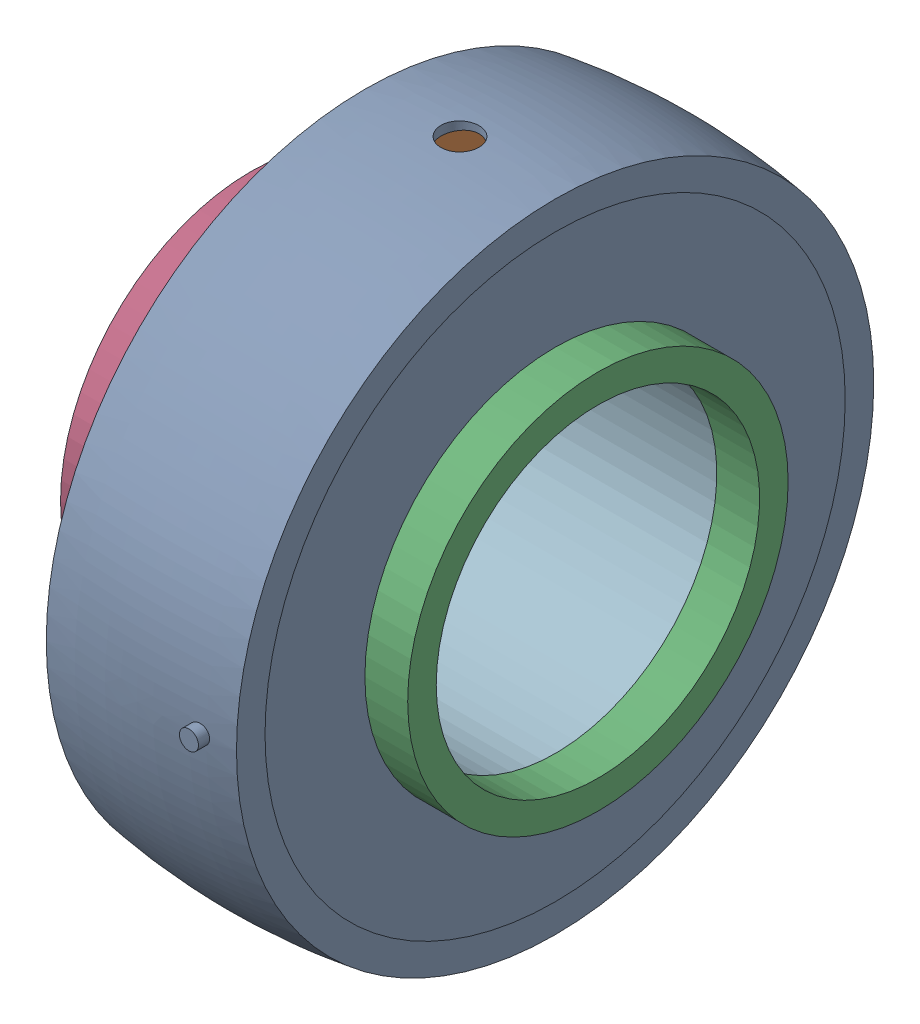
SolidWorks assembly PB bearing, configuration Default. Lengths in mm.
Overall size (36.5 72.34 70.23).
16 component instances, 6 part files, 0 mates.
Components (placement in the parent):
- PB outer-1: PB outer [Default] at origin size (20 68.56 69.24)
- PB Ball-1: PB Ball [Default] at (0 -4.1637 -25.6644) x (1 0 0) z (0 -0.951057 -0.309017) size (15 15 15)
- PB Ball-2: PB Ball [Default] at (0 -25.695 -3.9709) x (1 0 0) z (0 -0.587785 0.809017) size (15 15 15)
- PB Ball-3: PB Ball [Default] at (0 25.695 3.9709) x (1 0 0) z (0 0.587785 -0.809017) size (15 15 15)
- PB Ball-4: PB Ball [Default] at (0 -11.7167 23.2103) x (1 0 0) z (0 0.587785 0.809017) size (15 15 15)
- PB Ball-5: PB Ball [Default] at (0 11.7167 -23.2103) x (1 0 0) z (0 -0.587785 -0.809017) size (15 15 15)
- PB Ball-6: PB Ball [Default] at (0 23.1217 -11.8906) x (1 0 0) z (0 0 -1) size (15 15 15)
- PB Ball-7: PB Ball [Default] at (0 18.4537 18.3156) x (1 0 0) z (0 0.951057 -0.309017) size (15 15 15)
- PB Ball-8: PB Ball [Default] at (0 -23.1217 11.8906) size (15 15 15)
- PB Ball-9: PB Ball [Default] at (0 4.1637 25.6644) x (1 0 0) z (0 0.951057 0.309017) size (15 15 15)
- PB Ball-10: PB Ball [Default] at (0 -18.4537 -18.3156) x (1 0 0) z (0 -0.951057 0.309017) size (15 15 15)
- PB inner-1: PB inner [Default] at origin size (20 40 40)
- PB side cover-1: PB side cover [Default] at (10 0 0) x (0 -1 0) z (0 0 -1) size (61 1 61)
- PB side cover-2: PB side cover [Default] at (-10 0 0) x (0 -1 0) z (0 0 1) size (61 1 61)
- Rall inner ring A-1: Rall inner ring A [Default] at (10 0 0) x (0 -1 0) z (0 0 1) size (40 4.5 40)
- Rall inner ring B-1: Rall inner ring B [Default] at (-22 0 0) x (0 -1 0) z (0 0 1) size (40 12 40)
